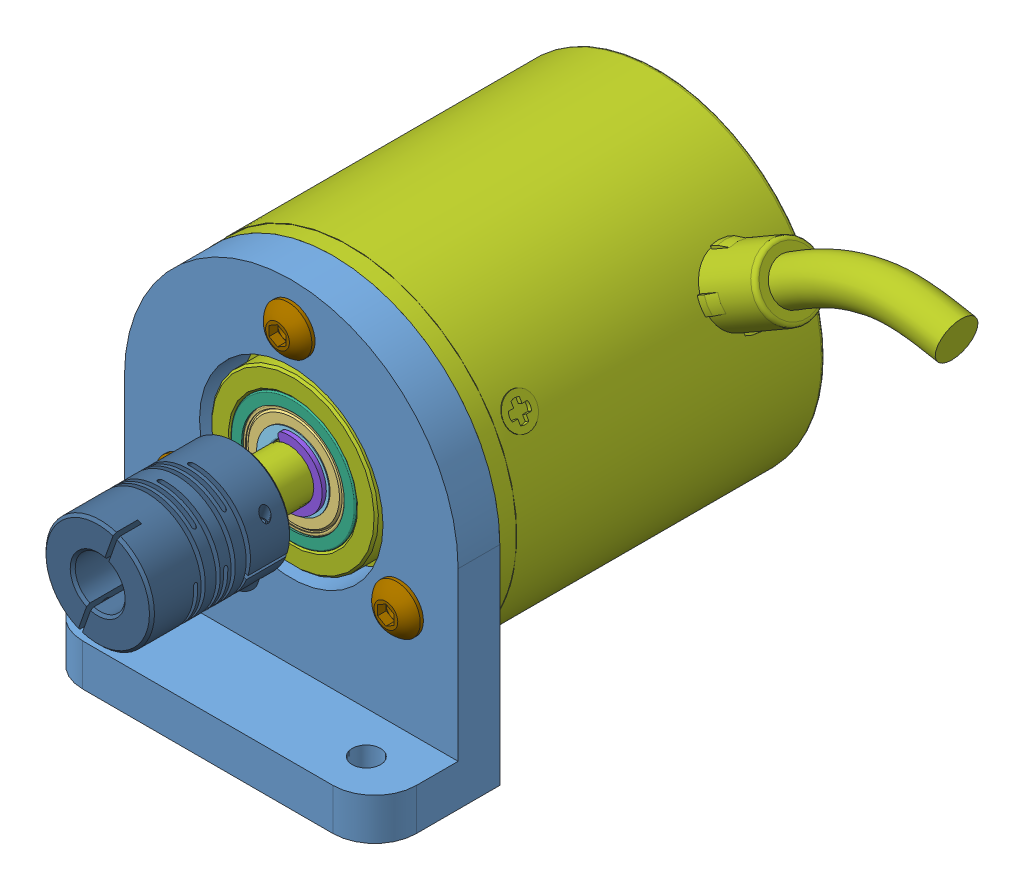
SolidWorks assembly Encoder mount, configuration Default. Lengths in mm.
Overall size (79.37 68.98 67.2).
14 component instances, 10 part files, 11 mates.
Components (placement in the parent):
- encoder mount-1: encoder mount [Default] at origin size (40 45 15)
- Enkoder YUMO E6B2-CWZ6C.stp-1: Enkoder YUMO E6B2-CWZ6C.stp [Default] at (0 0 4.8) x (-0.5 0.866025 0) z (0 0 1) size (40.1 68.5 58.4)
  - Łożysko 696.stp-1: Łożysko 696.stp [Default] x (0 0 -1) z (1 0 0) size (5 15 15)
    - bearing_696-zz_1_05.stp-1: bearing_696-zz_1_05.stp [Default] at origin size (0.3 12.3 12.3)
    - bearing_696-zz_1_04.stp-1: bearing_696-zz_1_04.stp [Default] at origin size (0.3 12.3 12.3)
    - bearing_696-zz_1_03.stp-1: bearing_696-zz_1_03.stp [Default] at origin size (3 13.5 13.5)
    - bearing_696-zz_1_02.stp-1: bearing_696-zz_1_02.stp [Default] at origin size (5 8.7 8.7)
    - bearing_696-zz_1_01.stp-1: bearing_696-zz_1_01.stp [Default] at origin size (5 15 15)
  - Enkoder YUMO E6B2-CWZ6C.stp-1: Enkoder YUMO E6B2-CWZ6C.stp [Default] at origin size (40.1 68.5 58.4)
  - Pierścień na wale enkodera YUMO.stp-1: Pierścień na wale enkodera YUMO.stp [Default] x (-0.782175 0.623059 0) z (0 0 1) size (8 5.8 0.5)
- socket button head screw_iso-2: socket button head screw_iso [ISO 7380 - M3 x 10 - 10N] at (12.9904 -7.5 6.65) x (0 0 -1) z (1 0 0) size (11.65 5.7 5.7)
- socket button head screw_iso-3: socket button head screw_iso [ISO 7380 - M3 x 10 - 10N] at (0 15 6.65) x (0 0 -1) z (1 0 0) size (11.65 5.7 5.7)
- socket button head screw_iso-4: socket button head screw_iso [ISO 7380 - M3 x 10 - 10N] at (-12.9904 -7.5 6.65) x (0 0 -1) z (1 0 0) size (11.65 5.7 5.7)
- 8011N214_Precision Flexible Shaft Coupling-1: 8011N214_Precision Flexible Shaft Coupling [8011N214] at (0 0 11.4) x (-0.334639 -0.942346 0) z (-0.942346 0.334639 0) size (13 16.8 13)
Mates (geometry in assembly coordinates):
- Coincident1: coincident anti-aligned: plane of encoder mount-1 through (0 0 0) normal (0 0 -1); plane of Enkoder YUMO E6B2-CWZ6C.stp-1/Enkoder YUMO E6B2-CWZ6C.stp-1 through (0 0 0) normal (0 0 1)
- Concentric2: concentric aligned: cylinder of encoder mount-1 through (0 0 5) axis (0 0 -1) radius 11; cylinder of Enkoder YUMO E6B2-CWZ6C.stp-1/Enkoder YUMO E6B2-CWZ6C.stp-1 through (0 0 0) axis (0 0 -1) radius 10
- Concentric3: concentric anti-aligned: cylinder of encoder mount-1 through (0 15 5) axis (0 0 1) radius 1.7; circle of Enkoder YUMO E6B2-CWZ6C.stp-1/Enkoder YUMO E6B2-CWZ6C.stp-1
- Concentric5: concentric aligned: cylinder of encoder mount-1 through (12.9904 -7.5 5) axis (0 0 1) radius 1.7; cylinder of socket button head screw_iso-2 through (12.9904 -7.5 6.65) axis (0 0 1) radius 2.85
- Coincident3: coincident anti-aligned: plane of encoder mount-1 through (0 0 5) normal (0 0 1); plane of socket button head screw_iso-2 through (12.9904 -6 5) normal (0 0 -1)
- Concentric6: concentric aligned: cylinder of encoder mount-1 through (0 15 5) axis (0 0 1) radius 1.7; cylinder of socket button head screw_iso-3 through (0 15 6.65) axis (0 0 1) radius 2.85
- Coincident4: coincident anti-aligned: plane of encoder mount-1 through (0 0 5) normal (0 0 1); plane of socket button head screw_iso-3 through (0 16.5 5) normal (0 0 -1)
- Concentric7: concentric aligned: cylinder of encoder mount-1 through (-12.9904 -7.5 5) axis (0 0 1) radius 1.7; cylinder of socket button head screw_iso-4 through (-12.9904 -7.5 6.65) axis (0 0 1) radius 2.85
- Coincident5: coincident anti-aligned: plane of encoder mount-1 through (0 0 5) normal (0 0 1); plane of socket button head screw_iso-4 through (-12.9904 -6 5) normal (0 0 -1)
- Concentric13: concentric anti-aligned: cylinder of Enkoder YUMO E6B2-CWZ6C.stp-1/Enkoder YUMO E6B2-CWZ6C.stp-1 through (0 0 4.8) axis (0 0 1) radius 3; cylinder of 8011N214_Precision Flexible Shaft Coupling-1 through (0 0 16) axis (0 0 -1) radius 2.5
- Distance2: distance = 8 mm anti-aligned: plane of 8011N214_Precision Flexible Shaft Coupling-1 through (0 0 11.4) normal (0 0 -1); plane of Enkoder YUMO E6B2-CWZ6C.stp-1/Enkoder YUMO E6B2-CWZ6C.stp-1 through (0 0 19.4) normal (0 0 1)
